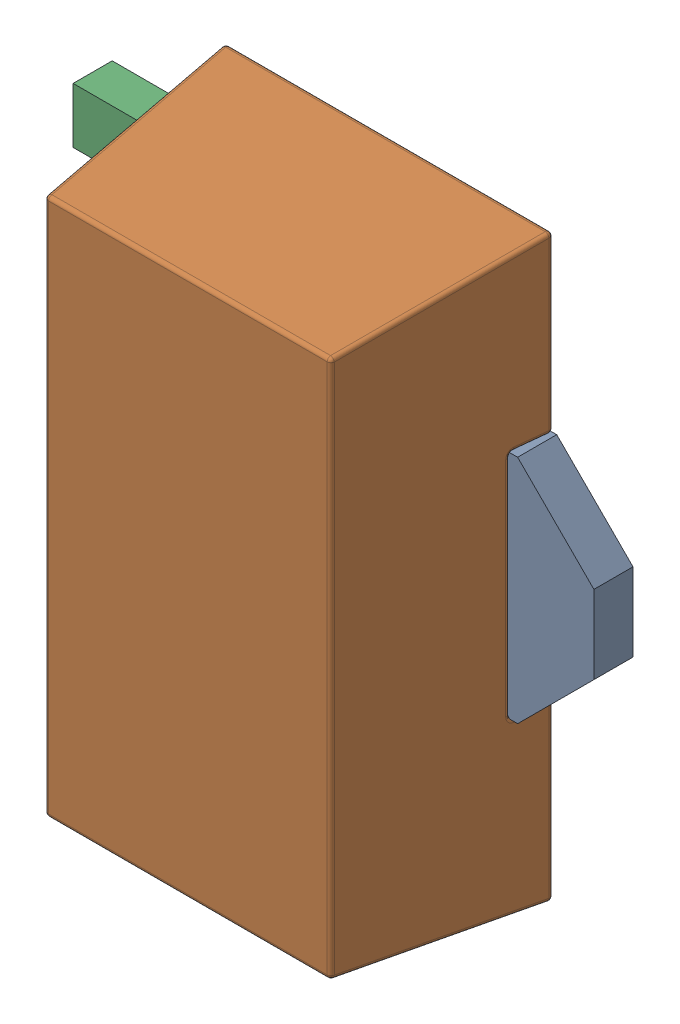
SolidWorks assembly 6297730608.step, configuration Default. Lengths in mm.
Overall size (4.13 4.59 1.6).
6 component instances, 4 part files, 0 mates.
Components (placement in the parent):
- CenterLeader.step-1: CenterLeader.step [Default] at (-1.3 -2.3 0) size (4.13 1.83 0.31)
  - Open CASCADE STEP translator 6.8 4.1.1.step-1: Open CASCADE STEP translator 6.8 4.1.1.step [Default] at origin size (4.13 1.83 0.31)
- Body (9).step-1: Body (9).step [Default] at (-1.3 -2.3 0) size (2.59 4.59 1.6)
  - Open CASCADE STEP translator 6.8 4.4.1.step-1: Open CASCADE STEP translator 6.8 4.4.1.step [Default] at origin size (2.59 4.59 1.6)
- top.step-1: top.step [Default] at (-1.3 -2.3 0) size (1.2 0.44 0.31)
- bottom.step-1: bottom.step [Default] at (-1.3 -2.3 0) size (1.2 0.44 0.31)
